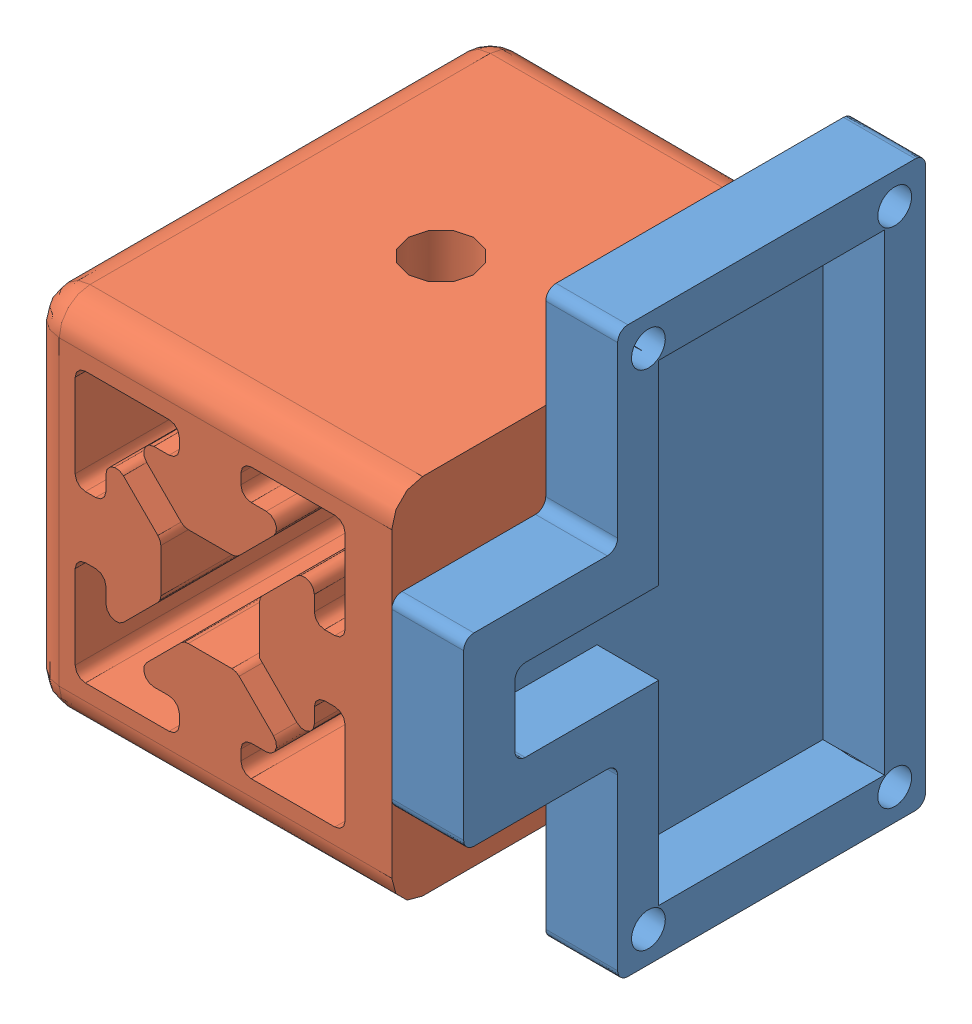
SolidWorks assembly FrontSensorHolder, configuration Default. Lengths in mm.
Overall size (42.4 55 45).
2 component instances, 2 part files, 3 mates.
Components (placement in the parent):
- 8020AttachmentSensorHolderBack-1: 8020AttachmentSensorHolderBack [Default] at (-46.5698 -30.4289 3.6805) size (24.55 55 45)
- 8020AttachmentTEst-1: 8020AttachmentTEst [Default] at (-58.2698 -2.9289 48.6805) x (1 0 0) z (0 1 0) size (35.4 45 35.4)
Mates (geometry in assembly coordinates):
- Coincident2: coincident anti-aligned: plane of 8020AttachmentSensorHolderBack-1 through (-40.5698 -29.4289 4.6805) normal (-1 0 0); plane of 8020AttachmentTEst-1 through (-40.5698 14.7711 -46.3827) normal (1 0 0)
- Coincident4: coincident aligned: plane of 8020AttachmentSensorHolderBack-1 through (-46.5698 -2.9289 3.6805) normal (0 1 0); plane of 8020AttachmentTEst-1 through (-58.2698 -2.9289 48.6805) normal (0 1 0)
- Coincident5: coincident aligned: plane of 8020AttachmentSensorHolderBack-1 through (-93.4635 6.0711 48.6805) normal (0 0 1); plane of 8020AttachmentTEst-1 through (-58.2698 -2.9289 48.6805) normal (0 0 1)
